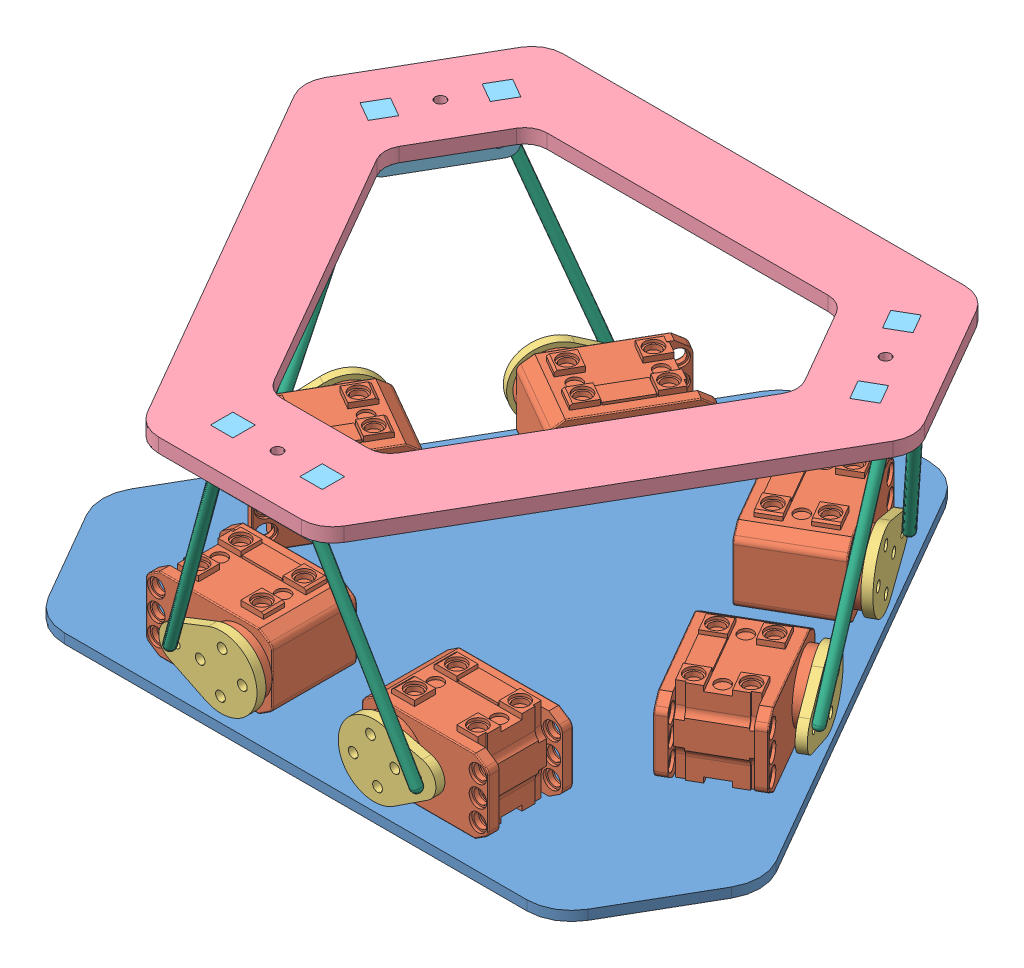
SolidWorks assembly ASM, SPRK 2, configuration Default. Lengths in mm.
Overall size (217.69 82.97 225.28).
24 component instances, 6 part files, 20 mates.
Components (placement in the parent):
- Stewart Base-2: Stewart Base [Default] at (125.7055 70.2946 140.5615) size (186.65 2.75 165.05)
- F_Dynamixel XL-320 with Standard Horn-1: F_Dynamixel XL-320 with Standard Horn [Default] at (147.4055 85.0446 190.3372) x (0 1 0) z (0 0 1) size (24 36 27)
- F_Dynamixel XL-320 with Standard Horn-7: F_Dynamixel XL-320 with Standard Horn [Default] at (104.0055 85.0446 190.3372) x (0 -1 0) z (0 0 1) size (24 36 27)
- F_Dynamixel XL-320 with Standard Horn-8: F_Dynamixel XL-320 with Standard Horn [Default] at (179.6625 85.0446 134.4664) x (0 -1 0) z (0.866025 0 -0.5) size (24 36 27)
- F_Dynamixel XL-320 with Standard Horn-9: F_Dynamixel XL-320 with Standard Horn [Default] at (93.4485 85.0446 96.8809) x (0 -1 0) z (-0.866025 0 -0.5) size (24 36 27)
- F_Dynamixel XL-320 with Standard Horn-5: F_Dynamixel XL-320 with Standard Horn [Default] at (157.9625 85.0446 96.8809) x (0 1 0) z (0.866025 0 -0.5) size (24 36 27)
- F_Dynamixel XL-320 with Standard Horn-6: F_Dynamixel XL-320 with Standard Horn [Default] at (71.7485 85.0446 134.4664) x (0 1 0) z (-0.866025 0 -0.5) size (24 36 27)
- Servo Horn for XL320-11: Servo Horn for XL320 [Default] at (147.4055 85.0446 207.8772) x (0.98576 0.168158 0) z (0 0 -1) size (27.94 20.32 2.54)
- Servo Horn for XL320-12: Servo Horn for XL320 [Default] at (104.0055 85.0446 207.8772) x (-0.999236 0.03908 0) z (0 0 -1) size (27.94 20.32 2.54)
- Servo Horn for XL320-13: Servo Horn for XL320 [Default] at (78.2584 85.0446 88.1109) x (0.5 0 -0.866025) z (0.866025 0 0.5) size (27.94 20.32 2.54)
- Servo Horn for XL320-14: Servo Horn for XL320 [Default] at (56.5584 85.0446 125.6964) x (-0.497812 -0.093453 0.862235) z (0.866025 0 0.5) size (27.94 20.32 2.54)
- Servo Horn for XL320-15: Servo Horn for XL320 [Default] at (194.8526 85.0446 125.6964) x (0.497564 -0.098582 0.861807) z (-0.866025 0 0.5) size (27.94 20.32 2.54)
- Servo Horn for XL320-16: Servo Horn for XL320 [Default] at (173.1526 85.0446 88.1109) x (-0.499986 0.007527 -0.866001) z (-0.866025 0 0.5) size (27.94 20.32 2.54)
- SubASM, Modular Top-1: SubASM, Modular Top [Default] at (116.1591 151.681 98.2737) x (0.5 0 -0.866025) z (0.866025 0 0.5) size (172.5 14.45 151.77)
  - Mounting Platform-1: Mounting Platform [Default] at (-31.8491 -2.4536 29.4113) size (172.5 4.04 151.77)
  - Ball Joint Housing Delrin-1: Ball Joint Housing Delrin [Default] at (34.142 -12.8676 67.5113) x (-0.5 0 0.866025) z (-0.866025 0 -0.5) size (31.75 14.45 6.35)
  - Ball Joint Housing Delrin-2: Ball Joint Housing Delrin [Default] at (-31.8491 -12.8676 -46.7887) size (31.75 14.45 6.35)
  - Ball Joint Housing Delrin-3: Ball Joint Housing Delrin [Default] at (-97.8402 -12.8676 67.5113) x (-0.5 0 -0.866025) z (0.866025 0 -0.5) size (31.75 14.45 6.35)
- M3 Ball Joint Rod-2: M3 Ball Joint Rod [Default] at (198.6768 145.0276 113.6432) x (0.06194 -0.930394 0.361291) z (0.503268 0.341713 0.793696) size (66.5 3 3)
- M3 Ball Joint Rod-8: M3 Ball Joint Rod [Default] at (185.5031 145.0276 90.8256) x (-0.281917 -0.930394 -0.234287) z (0.435727 -0.341713 0.832691) size (66.5 3 3)
- M3 Ball Joint Rod-9: M3 Ball Joint Rod [Default] at (52.7342 145.0276 113.6432) x (-0.06194 -0.930394 0.361291) z (0.503268 -0.341713 -0.793696) size (66.5 3 3)
- M3 Ball Joint Rod-10: M3 Ball Joint Rod [Default] at (138.8793 145.0276 217.2156) x (0.343857 -0.930394 -0.127003) z (-0.938995 -0.341713 -0.038995) size (66.5 3 3)
- M3 Ball Joint Rod-6: M3 Ball Joint Rod [Default] at (65.908 145.0276 90.8256) x (0.281917 -0.930394 -0.234287) z (0.435727 0.341713 -0.832691) size (66.5 3 3)
- M3 Ball Joint Rod-7: M3 Ball Joint Rod [Default] at (112.5318 145.0276 217.2156) x (-0.343857 -0.930394 -0.127003) z (-0.938995 0.341713 0.038995) size (66.5 3 3)
Mates (geometry in assembly coordinates):
- Concentric1: concentric anti-aligned: cylinder of Stewart Base-2 through (165.4055 70.2946 196.3372) axis (0 1 0) radius 1.3891; cylinder of F_Dynamixel XL-320 with Standard Horn-1 through (165.4055 73.0446 196.3372) axis (0 -1 0) radius 2.5
- Concentric2: concentric anti-aligned: cylinder of Stewart Base-2 through (147.4055 70.2946 196.3372) axis (0 1 0) radius 1.3891; cylinder of F_Dynamixel XL-320 with Standard Horn-1 through (147.4055 73.0446 196.3372) axis (0 -1 0) radius 2
- Coincident1: coincident anti-aligned: plane of Stewart Base-2 through (125.7055 73.0446 140.5615) normal (0 1 0); plane of F_Dynamixel XL-320 with Standard Horn-1 through (147.4055 73.0446 190.3372) normal (0 -1 0)
- Concentric3: concentric anti-aligned: cylinder of Stewart Base-2 through (104.0055 70.2946 196.3372) axis (0 1 0) radius 1.3891; cylinder of F_Dynamixel XL-320 with Standard Horn-7 through (104.0055 73.0446 196.3372) axis (0 -1 0) radius 2.5
- Concentric4: concentric anti-aligned: cylinder of Stewart Base-2 through (86.0055 70.2946 196.3372) axis (0 1 0) radius 1.3891; cylinder of F_Dynamixel XL-320 with Standard Horn-7 through (86.0055 73.0446 196.3372) axis (0 -1 0) radius 2
- Coincident2: coincident anti-aligned: plane of Stewart Base-2 through (125.7055 73.0446 140.5615) normal (0 1 0); plane of F_Dynamixel XL-320 with Standard Horn-7 through (104.0055 73.0446 190.3372) normal (0 -1 0)
- Coincident3: coincident anti-aligned: plane of F_Dynamixel XL-320 with Standard Horn-1 through (147.4055 87.8446 205.3372) normal (0 0 1); plane of Servo Horn for XL320-11 through (147.4055 85.0446 205.3372) normal (0 0 -1)
- Concentric5: concentric anti-aligned: cylinder of F_Dynamixel XL-320 with Standard Horn-1 through (147.4055 85.0446 202.3372) axis (0 0 1) radius 2.8; circle of Servo Horn for XL320-11
- Coincident5: coincident anti-aligned: plane of F_Dynamixel XL-320 with Standard Horn-7 through (104.0055 82.2446 205.3372) normal (0 0 1); plane of Servo Horn for XL320-12 through (104.0055 85.0446 205.3372) normal (0 0 -1)
- Concentric6: concentric anti-aligned: cylinder of F_Dynamixel XL-320 with Standard Horn-7 through (104.0055 85.0446 202.3372) axis (0 0 1) radius 2.8; circle of Servo Horn for XL320-12
- Coincident7: coincident anti-aligned: plane of F_Dynamixel XL-320 with Standard Horn-6 through (58.7582 87.8446 126.9664) normal (-0.866025 0 -0.5); plane of Servo Horn for XL320-14 through (58.7582 85.0446 126.9664) normal (0.866025 0 0.5)
- Concentric7: concentric anti-aligned: cylinder of F_Dynamixel XL-320 with Standard Horn-6 through (61.3562 85.0446 128.4664) axis (-0.866025 0 -0.5) radius 2.8; circle of Servo Horn for XL320-14
- Coincident9: coincident anti-aligned: plane of F_Dynamixel XL-320 with Standard Horn-9 through (80.4582 82.2446 89.3809) normal (-0.866025 0 -0.5); plane of Servo Horn for XL320-13 through (80.4582 85.0446 89.3809) normal (0.866025 0 0.5)
- Coincident10: coincident anti-aligned: cylinder of F_Dynamixel XL-320 with Standard Horn-9 through (83.0562 85.0446 90.8809) axis (-0.866025 0 -0.5) radius 2.8; circle of Servo Horn for XL320-13
- Coincident11: coincident anti-aligned: plane of F_Dynamixel XL-320 with Standard Horn-5 through (170.9529 87.8446 89.3809) normal (0.866025 0 -0.5); plane of Servo Horn for XL320-16 through (170.9529 85.0446 89.3809) normal (-0.866025 0 0.5)
- Concentric8: concentric anti-aligned: cylinder of F_Dynamixel XL-320 with Standard Horn-5 through (168.3548 85.0446 90.8809) axis (0.866025 0 -0.5) radius 2.8; circle of Servo Horn for XL320-16
- Coincident13: coincident anti-aligned: plane of F_Dynamixel XL-320 with Standard Horn-8 through (192.6529 82.2446 126.9664) normal (0.866025 0 -0.5); plane of Servo Horn for XL320-15 through (192.6529 85.0446 126.9664) normal (-0.866025 0 0.5)
- Concentric9: concentric anti-aligned: cylinder of F_Dynamixel XL-320 with Standard Horn-8 through (190.0548 85.0446 128.4664) axis (0.866025 0 -0.5) radius 2.8; circle of Servo Horn for XL320-15
- Coincident14: coincident aligned: line of SubASM, Modular Top-1 through (125.7055 153.2659 140.5615) axis (0 1 0); line of assembly
- Parallel1: parallel aligned: plane of Stewart Base-2 through (147.9708 73.0446 43.3846) normal (0.866025 0 -0.5); plane of SubASM, Modular Top-1/Ball Joint Housing Delrin-1 through (191.6967 138.8133 102.4615) normal (0.866025 0 -0.5)
